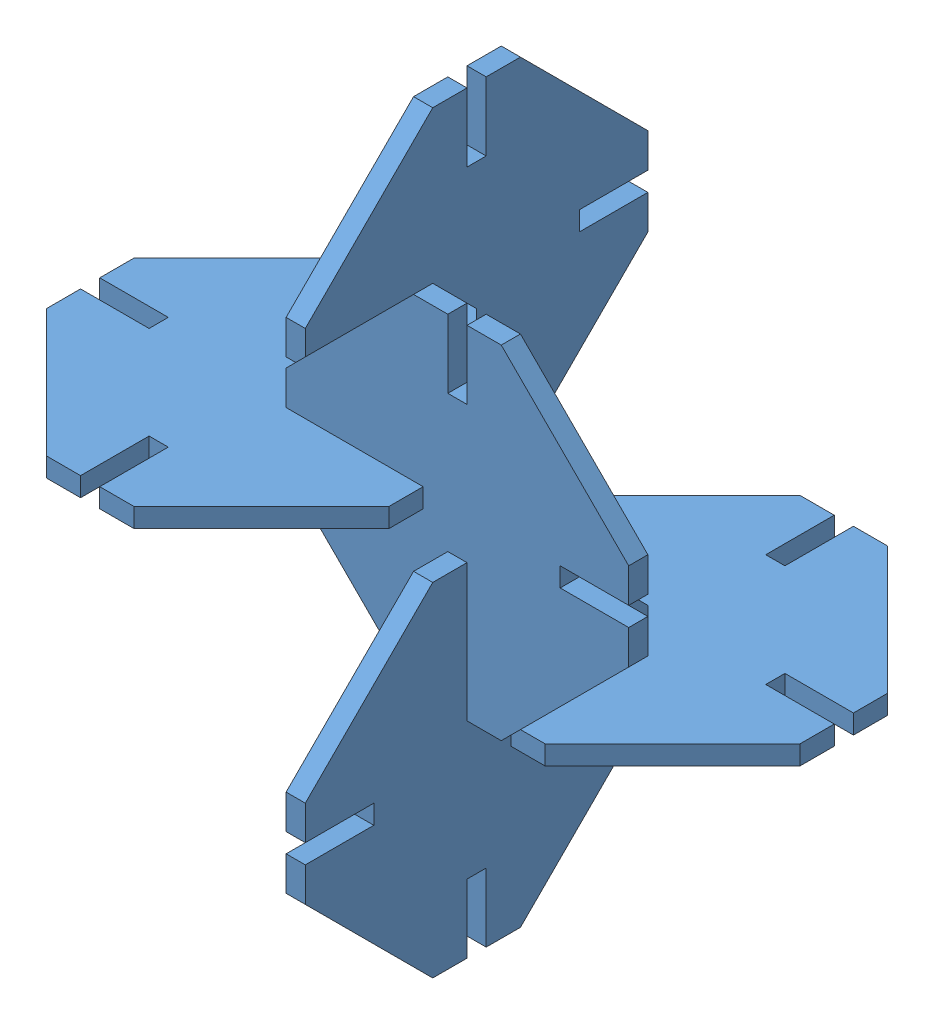
SolidWorks assembly Parametric assembly, configuration Default. Lengths in mm.
Overall size (80 80 80).
6 component instances, 1 part files, 17 mates.
Components (placement in the parent):
- Parametric kit-1: Parametric kit [Default] at origin size (50 50 2.8)
- Parametric kit-2: Parametric kit [Default] at (-1.4 30 1.4) x (0 0 -1) z (1 0 0) size (50 50 2.8)
- Parametric kit-3: Parametric kit [Default] at (30 1.4 1.4) x (1 0 0) z (0 -1 0) size (50 50 2.8)
- Parametric kit-4: Parametric kit [Default] at (28.6 0 31.4) x (0 -1 0) z (1 0 0) size (50 50 2.8)
- Parametric kit-6: Parametric kit [Default] at (0 31.4 31.4) x (-1 0 0) z (0 -1 0) size (50 50 2.8)
- Parametric kit-7: Parametric kit [Default] at (30 30 32.8) x (0 -1 0) z (0 0 -1) size (50 50 2.8)
Mates (geometry in assembly coordinates):
- Coincident1: coincident aligned: plane of Parametric kit-1 through (0 0 0) normal (0 0 1)
- Coincident2: coordinate: point of Parametric kit-1
- Coincident3: coincident anti-aligned: plane of Parametric kit-1 through (0 0 0) normal (0 0 -1); plane of Parametric kit-2 through (1.4 5 0) normal (0 0 1)
- Coincident4: coincident anti-aligned: plane of Parametric kit-1 through (-1.4 25 2.8) normal (1 0 0); plane of Parametric kit-2 through (-1.4 30 1.4) normal (-1 0 0)
- Coincident5: coincident anti-aligned: plane of Parametric kit-1 through (0 0 0) normal (0 0 -1); plane of Parametric kit-3 through (15 -1.4 0) normal (0 0 1)
- Coincident6: coincident anti-aligned: plane of Parametric kit-1 through (15 -1.4 2.8) normal (0 1 0); plane of Parametric kit-3 through (30 -1.4 1.4) normal (0 -1 0)
- Coincident7: coincident anti-aligned: plane of Parametric kit-1 through (-1.4 15 2.8) normal (0 1 0); plane of Parametric kit-2 through (1.4 15 2.8) normal (0 -1 0)
- Coincident8: coincident anti-aligned: plane of Parametric kit-1 through (15 -1.4 2.8) normal (1 0 0); plane of Parametric kit-3 through (15 -1.4 0) normal (-1 0 0)
- Coincident11: coincident anti-aligned: plane of Parametric kit-3 through (30 -1.4 1.4) normal (0 -1 0); plane of Parametric kit-4 through (31.4 -1.4 6.4) normal (0 1 0)
- Coincident12: coincident anti-aligned: plane of Parametric kit-3 through (28.6 -1.4 16.4) normal (0 0 1); plane of Parametric kit-4 through (31.4 1.4 16.4) normal (0 0 -1)
- Coincident13: coincident anti-aligned: plane of Parametric kit-3 through (31.4 -1.4 26.4) normal (-1 0 0); plane of Parametric kit-4 through (31.4 0 31.4) normal (1 0 0)
- Coincident14: coincident: plane of Parametric kit-2 through (1.4 28.6 16.4) normal (0 1 0); plane of Parametric kit-6 through (0 28.6 31.4) normal (0 -1 0)
- Coincident15: coincident: plane of Parametric kit-2 through (1.4 28.6 16.4) normal (0 0 1); plane of Parametric kit-6 through (1.4 28.6 16.4) normal (0 0 -1)
- Coincident16: coincident anti-aligned: plane of Parametric kit-2 through (-1.4 30 1.4) normal (-1 0 0); plane of Parametric kit-6 through (-1.4 28.6 6.4) normal (1 0 0)
- Coincident18: coincident: plane of Parametric kit-6 through (15 28.6 30) normal (0 0 1); plane of Parametric kit-7 through (30.3079 50 29.7592) normal (0 0 -1)
- Coincident19: coincident: plane of Parametric kit-6 through (15 28.6 32.8) normal (1 0 0); plane of Parametric kit-7 through (15.3079 51.4 29.7592) normal (-1 0 0)
- Coincident20: coincident anti-aligned: plane of Parametric kit-4 through (31.4 15 32.8) normal (0 1 0); plane of Parametric kit-7 through (31.7079 35 29.7592) normal (0 -1 0)
